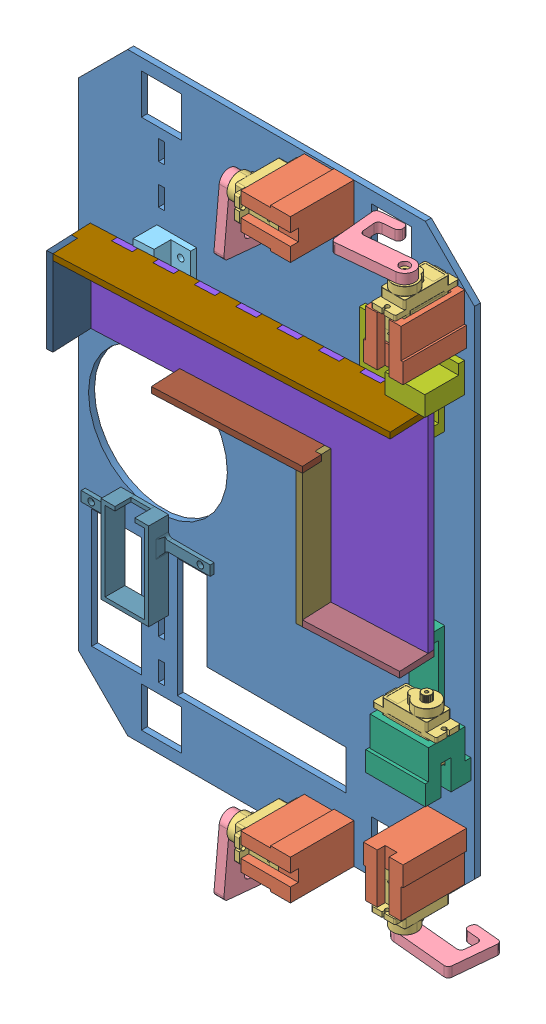
SolidWorks assembly Assemblage deuxieme etage Robot 2, configuration Défaut. Lengths in mm.
Overall size (217.24 321.24 38.73).
29 component instances, 14 part files, 35 mates.
Components (placement in the parent):
- Plaque robot deuxième étage V.1-1: Plaque robot deuxième étage V.1 [Défaut] at (-35.509 206.8367 573.423) x (-1 0 0) z (0 0 1) size (199.5 299.5 3)
- Assemblage Servo-Support Servo-1: Assemblage Servo-Support Servo [Défaut] at (108.491 -82.5809 591.4643) x (0 0 -1) z (-1 0 0) size (32.1 41.74 41.75)
  - Support Servo-1: Support Servo [Défaut] at (-0.9587 0.0799 30) size (32 20 25)
  - SG90 Servo-1: SG90 Servo [Défaut] at (-7.6319 27.8631 33.7322) x (1 0 0) z (0 -1 0) size (32.1 29.95 12.4)
  - Crochet-1: Crochet [Défaut] at (-7.5154 15.0138 66.75) x (-0.093785 0.995592 0) z (0 0 1) size (35 25 5)
- Assemblage Servo-Support Servo-2: Assemblage Servo-Support Servo [Défaut] at (125.3196 131.8367 591.4643) x (0 0 -1) z (0 1 0) size (32.1 41.74 41.75)
  - Support Servo-1: Support Servo [Défaut] at (-0.9587 0.0799 30) size (32 20 25)
  - SG90 Servo-1: SG90 Servo [Défaut] at (-7.6319 27.8631 33.7322) x (1 0 0) z (0 -1 0) size (32.1 29.95 12.4)
  - Crochet-1: Crochet [Défaut] at (-7.5154 15.0138 66.75) x (-0.093785 0.995592 0) z (0 0 1) size (35 25 5)
- Assemblage Servo-Support Servo-3: Assemblage Servo-Support Servo [Défaut] at (125.1598 -17.6608 591.4643) x (0 0 -1) z (0 -1 0) size (32.1 41.74 41.75)
  - Support Servo-1: Support Servo [Défaut] at (-0.9587 0.0799 30) size (32 20 25)
  - SG90 Servo-1: SG90 Servo [Défaut] at (-7.6319 27.8631 33.7322) x (1 0 0) z (0 -1 0) size (32.1 29.95 12.4)
  - Crochet-1: Crochet [Défaut] at (-7.5154 15.0138 66.75) x (-0.093785 0.995592 0) z (0 0 1) size (35 25 5)
- Assemblage Servo-Support Servo-4: Assemblage Servo-Support Servo [Défaut] at (108.491 196.9165 591.4643) x (0 0 -1) z (-1 0 0) size (32.1 41.74 41.75)
  - Support Servo-1: Support Servo [Défaut] at (-0.9587 0.0799 30) size (32 20 25)
  - SG90 Servo-1: SG90 Servo [Défaut] at (-7.6319 27.8631 33.7322) x (1 0 0) z (0 -1 0) size (32.1 29.95 12.4)
  - Crochet-1: Crochet [Défaut] at (-7.5154 15.0138 66.75) x (-0.093785 0.995592 0) z (0 0 1) size (35 25 5)
- Support pente first-1: Support pente first [Défaut] at (-20.7603 96.6867 576.423) x (0 1 0) z (0 0 1) size (41 20 12)
- Support pente pièce 1-1: Support pente pièce 1 [Défaut] at (124.2397 30.2889 583.423) x (-1 0 0) z (0 1 0) size (53.2 23 61)
- Support pente pièce 2-1: Support pente pièce 2 [Défaut] at (84.2397 120.0184 583.423) x (0 0 -1) z (0 1 0) size (20 50 36)
- SG90 Servo-3: SG90 Servo [Défaut] at (128.963 -21.9789 616.5062) x (-1 0 0) z (0 0 -1) size (32.1 29.95 12.4)
- stockage cerises-1: stockage cerises [Défaut] at (41.9568 79.5685 419.3606) x (0.999046 0 -0.043662) z (0.043662 0 0.999046) size (166 110 23)
  - Pente stockage cerise-1: Pente stockage cerise [Défaut] at (-87.8934 54.8582 166) size (166 110 3)
  - Mur extérieur pente cerise-1: Mur extérieur pente cerise [Défaut] at (-87.8934 54.8582 189) x (1 0 0) z (0 -1 0) size (166 23 3)
  - Mur haut pente cerise-1: Mur haut pente cerise [Défaut] at (-90.8934 11.8582 189) x (0 1 0) z (1 0 0) size (43 23 3)
  - Mur intérieur 1 pente cerise-1: Mur intérieur 1 pente cerise [Défaut] at (-44.8934 14.8582 184) x (1 0 0) z (0 -1 0) size (73 18 3)
  - Mur intérieur 2 pente cerise-1: Mur intérieur 2 pente cerise [Défaut] at (25.1066 -52.1418 184) x (0 1 0) z (1 0 0) size (70 18 3)
  - Mur intérieur 3 pente cerise-1: Mur intérieur 3 pente cerise [Défaut] at (25.1066 -52.1418 184) x (1 0 0) z (0 -1 0) size (50 18 3)
- suport servo modifié-1: suport servo modifié [Défaut] at (-56.9078 4.6867 576.423) x (0 -1 0) z (-1 0 0) size (44 10 65)
Mates (geometry in assembly coordinates):
- Coïncidente95: coincident anti-aligned: plane of SG90 Servo-1 through (82.2791 -10.8598 645.789) normal (-0.161572 0.718869 0.676108); plane of Bras sortie de billes-1 through (48.9167 -7.7483 634.5079) normal (0.161572 -0.718869 -0.676108)
- Coaxiale41: concentric anti-aligned: circle of SG90 Servo-1; cylinder of Bras sortie de billes-1 through (81.4713 -7.2655 649.1695) axis (0.161572 -0.718869 -0.676108) radius 3.125
- Coïncidente97: coincident anti-aligned: circle of Support pente pièce 2-1; circle of Bras porte cerises fixation axe-1
- Coïncidente115: coincident anti-aligned: plane of Pente pièce 4-1 through (-7.0744 -32.1546 574.4556) normal (0.865944 0.43187 -0.252247); plane of Support pente pièce 2-1 through (84.2397 120.0184 583.423) normal (0.037474 0 0.999298)
- Parallèle9: parallel aligned: plane of Pente pièce 4-1 through (-9.6723 -33.4502 575.2123) normal (-0.161572 0.718869 0.676108); plane of Support pente pièce 2-1 through (84.2397 125.0184 583.423) normal (0 1 0)
- Distance3: distance = 8 mm aligned: plane of Support pente pièce 2-1 through (84.2397 125.0184 583.423) normal (0 1 0); plane of Pente pièce 4-1 through (-9.6723 -33.4502 575.2123) normal (-0.161572 0.718869 0.676108)
- Coïncidente145: coincident anti-aligned: circle of Plaque robot deuxième étage V.1-1; circle of Assemblage Servo-Support Servo-1/Support Servo-1
- Coaxiale42: concentric anti-aligned: circle of Plaque robot deuxième étage V.1-1; circle of Assemblage Servo-Support Servo-1/Support Servo-1
- Coïncidente149: coincident anti-aligned: circle of Plaque robot deuxième étage V.1-1; circle of Assemblage Servo-Support Servo-3/Support Servo-1
- Coaxiale44: concentric anti-aligned: circle of Plaque robot deuxième étage V.1-1; circle of Assemblage Servo-Support Servo-3/Support Servo-1
- Coïncidente153: coincident anti-aligned: circle of Plaque robot deuxième étage V.1-1; circle of Assemblage Servo-Support Servo-2/Support Servo-1
- Coaxiale45: concentric anti-aligned: circle of Plaque robot deuxième étage V.1-1; circle of Assemblage Servo-Support Servo-2/Support Servo-1
- Coïncidente160: coincident anti-aligned: circle of Plaque robot deuxième étage V.1-1; circle of Assemblage Servo-Support Servo-4/Support Servo-1
- Coaxiale46: concentric anti-aligned: circle of Plaque robot deuxième étage V.1-1; circle of Assemblage Servo-Support Servo-4/Support Servo-1
- Parallèle11: parallel anti-aligned: plane of plaque_cartes_éléctroniques_2-1 through (-85.6262 126.0582 579.7101) normal (-1 0 0); plane of CIRCUIT BOARD,TEENSY 4.10-1 through (-95.6262 -84.4126 471.1676) normal (1 0 0)
- Distance11: distance = 10 mm anti-aligned: plane of CIRCUIT BOARD,TEENSY 4.10-1 through (-95.6262 -84.4126 471.1676) normal (1 0 0); plane of plaque_cartes_éléctroniques_2-1 through (-85.6262 126.0582 579.7101) normal (-1 0 0)
- Parallèle12: parallel aligned: plane of plaque_cartes_éléctroniques_2-1 through (-82.6262 126.0582 399.7101) normal (0 0 -1); plane of CIRCUIT BOARD,TEENSY 4.10-1 through (-97.2242 -100.9226 411.4776) normal (0 0 -1)
- Parallèle13: parallel anti-aligned: plane of plaque_cartes_éléctroniques_2-1 through (-85.6262 126.0582 579.7101) normal (-1 0 0); plane of Raspberry Pi 4 Model B-1 through (-90.6262 -76.0331 525.4361) normal (1 0 0)
- Parallèle14: parallel aligned: plane of plaque_cartes_éléctroniques_2-1 through (-82.6262 126.0582 399.7101) normal (0 0 -1); plane of Raspberry Pi 4 Model B-1 through (-92.2262 -48.0331 482.9361) normal (0 0 -1)
- Distance12: distance = 5 mm anti-aligned: plane of Raspberry Pi 4 Model B-1 through (-90.6262 -76.0331 525.4361) normal (1 0 0); plane of plaque_cartes_éléctroniques_2-1 through (-85.6262 126.0582 579.7101) normal (-1 0 0)
- Coïncidente185: coincident aligned: circle of Plaque robot deuxième étage V.1-1; circle of Support pente pièce 2-1
- Coïncidente186: coincident aligned: circle of Plaque robot deuxième étage V.1-1; circle of Support pente pièce 2-1
- Coïncidente187: coincident aligned: circle of Plaque robot deuxième étage V.1-1; circle of Support pente pièce 1-1
- Coïncidente188: coincident aligned: circle of Plaque robot deuxième étage V.1-1; circle of Support pente pièce 1-1
- Coïncidente189: coincident aligned: circle of Plaque robot deuxième étage V.1-1; circle of Support pente first-1
- Coïncidente190: coincident aligned: circle of Plaque robot deuxième étage V.1-1; cylinder of Support pente first-1 through (-5.7603 102.1867 569.423) axis (0 0 1) radius 1.625
- Coïncidente191: coincident anti-aligned: plane of Support pente pièce 1-1 through (137.4397 -15.7111 579.423) normal (0 1 0); plane of SG90 Servo-3 through (132.6897 -15.7111 583.473) normal (0 -1 0)
- Coïncidente192: coincident anti-aligned: plane of Support pente pièce 1-1 through (111.0397 -0.7111 594.823) normal (0 0 -1); plane of SG90 Servo-3 through (137.4897 2.4889 594.823) normal (0 0 1)
- Coïncidente193: coincident anti-aligned: plane of Support pente pièce 1-1 through (111.0397 -0.7111 594.823) normal (1 0 0); plane of SG90 Servo-3 through (111.0397 -0.0111 583.473) normal (-1 0 0)
- Coïncidente199: coincident anti-aligned: line of Support pente pièce 2-1 through (124.2397 120.0184 581.923) axis (0 1 0); line of stockage cerises-1/Pente stockage cerise-1 through (124.2397 134.4267 581.923) axis (0 -1 0)
- Coïncidente201: coincident: line of Support pente first-1 through (-10.7603 96.6867 587.823) axis (0 1 0); plane of stockage cerises-1/Pente stockage cerise-1 through (-38.6048 134.4267 589.0399) normal (-0.043662 0 -0.999046)
- Coaxiale49: concentric anti-aligned: cylinder of Plaque robot deuxième étage V.1-1 through (-51.9078 2.1867 573.422) axis (0 0 1) radius 1.625; cylinder of suport servo modifié-1 through (-51.9078 2.1867 586.423) axis (0 0 -1) radius 1.65
- Coaxiale50: concentric anti-aligned: cylinder of Plaque robot deuxième étage V.1-1 through (3.0922 2.1867 573.422) axis (0 0 1) radius 1.625; cylinder of suport servo modifié-1 through (3.0922 2.1867 586.423) axis (0 0 -1) radius 1.65
- Coïncidente210: coincident anti-aligned: plane of Plaque robot deuxième étage V.1-1 through (-35.509 206.8367 576.423) normal (0 0 1); plane of suport servo modifié-1 through (-56.9078 4.6867 576.423) normal (0 0 -1)
- Verrouiller1: lock: unknown of Plaque robot deuxième étage V.1-1; unknown of stockage cerises-1/Pente stockage cerise-1
